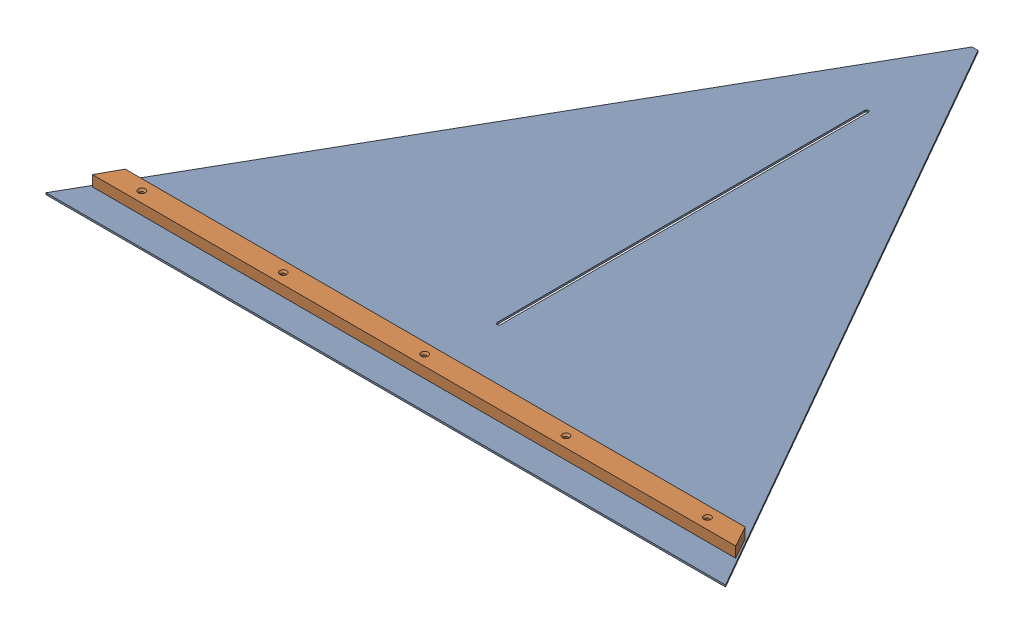
SolidWorks assembly GE-16185_ASM, configuration Default. Lengths in mm.
Overall size (1220.65 22.23 1058.51).
2 component instances, 2 part files, 0 mates.
Components (placement in the parent):
- GE-16143-1: GE-16143 [Default] at origin size (1220.65 3.17 1058.51)
- GE-16184-1: GE-16184 [Default] at (0 3.175 1007.7064) x (1 0 0) z (0 1 0) size (1155.7 38.1 19.05)
